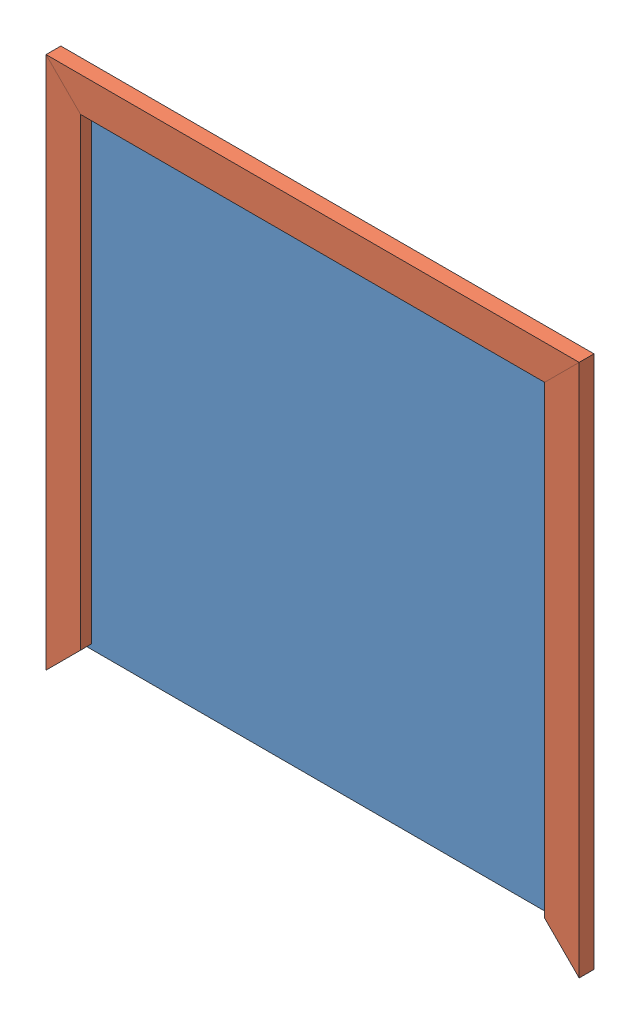
SolidWorks assembly Assem2, configuration Default. Lengths in mm.
Overall size (1371.6 1371.6 38.1).
4 component instances, 2 part files, 12 mates.
Components (placement in the parent):
- Blackboard-1: Blackboard [Default] at origin size (1219.2 1219.2 9.53)
- blackboard 2X4-1: blackboard 2X4 [Default] at (1206.5 -76.2 38.1) x (0 1 0) z (0 0 -1) size (1371.6 88.9 38.1)
- blackboard 2X4-2: blackboard 2X4 [Default] at (1295.4 1206.5 38.1) x (-1 0 0) z (0 0 -1) size (1371.6 88.9 38.1)
- blackboard 2X4-3: blackboard 2X4 [Default] at (12.7 1295.4 38.1) x (0 -1 0) z (0 0 -1) size (1371.6 88.9 38.1)
Mates (geometry in assembly coordinates):
- Parallel7: parallel aligned: plane of Blackboard-1 through (0 0 9.525) normal (0 0 1); plane of blackboard 2X4-2 through (1295.4 1206.5 38.1) normal (0 0 1)
- Parallel8: parallel anti-aligned: line of Blackboard-1 through (1219.2 1219.2 1219.2) axis (0 -1 0); line of blackboard 2X4-2 through (-76.2 1295.4 0) axis (1 0 0)
- Coincident19: coincident anti-aligned: line of Blackboard-1 through (1219.2 1219.2 1219.2) axis (0 -1 0); line of blackboard 2X4-2 through (0 1219.2 0) axis (1 0 0)
- Coincident20: coincident aligned: line of Blackboard-1 through (0 1219.2 9.525) axis (0 0 -1); line of blackboard 2X4-2 through (0 1219.2 9.525) axis (0 0 -1)
- Parallel11: parallel aligned: plane of Blackboard-1 through (0 0 0) normal (0 0 -1); plane of blackboard 2X4-3 through (12.7 1295.4 0) normal (0 0 -1)
- Parallel12: parallel anti-aligned: plane of Blackboard-1 through (0 0 9.525) normal (-1 0 0); plane of blackboard 2X4-3 through (12.7 1295.4 0) normal (1 0 0)
- Coincident25: coincident anti-aligned: line of Blackboard-1 through (1219.2 0 1219.2) axis (0 0 -1); line of blackboard 2X4-3 through (0 0 0) axis (0 1 0)
- Coincident26: coincident aligned: line of blackboard 2X4-2 through (-76.2 1295.4 0) axis (0 0 1); line of blackboard 2X4-3 through (-76.2 1295.4 0) axis (0 0 1)
- Parallel13: parallel aligned: plane of Blackboard-1 through (0 0 9.525) normal (0 0 1); plane of blackboard 2X4-1 through (1206.5 -76.2 38.1) normal (0 0 1)
- Parallel14: parallel anti-aligned: plane of Blackboard-1 through (1219.2 0 9.525) normal (1 0 0); plane of blackboard 2X4-1 through (1206.5 -76.2 0) normal (-1 0 0)
- Coincident29: coincident anti-aligned: line of Blackboard-1 through (1219.2 1219.2 0) axis (0 0 1); line of blackboard 2X4-1 through (1219.2 1219.2 0) axis (0 -1 0)
- Coincident30: coincident aligned: line of blackboard 2X4-1 through (1295.4 1295.4 0) axis (0 0 1); line of blackboard 2X4-2 through (1295.4 1295.4 0) axis (0 0 1)
